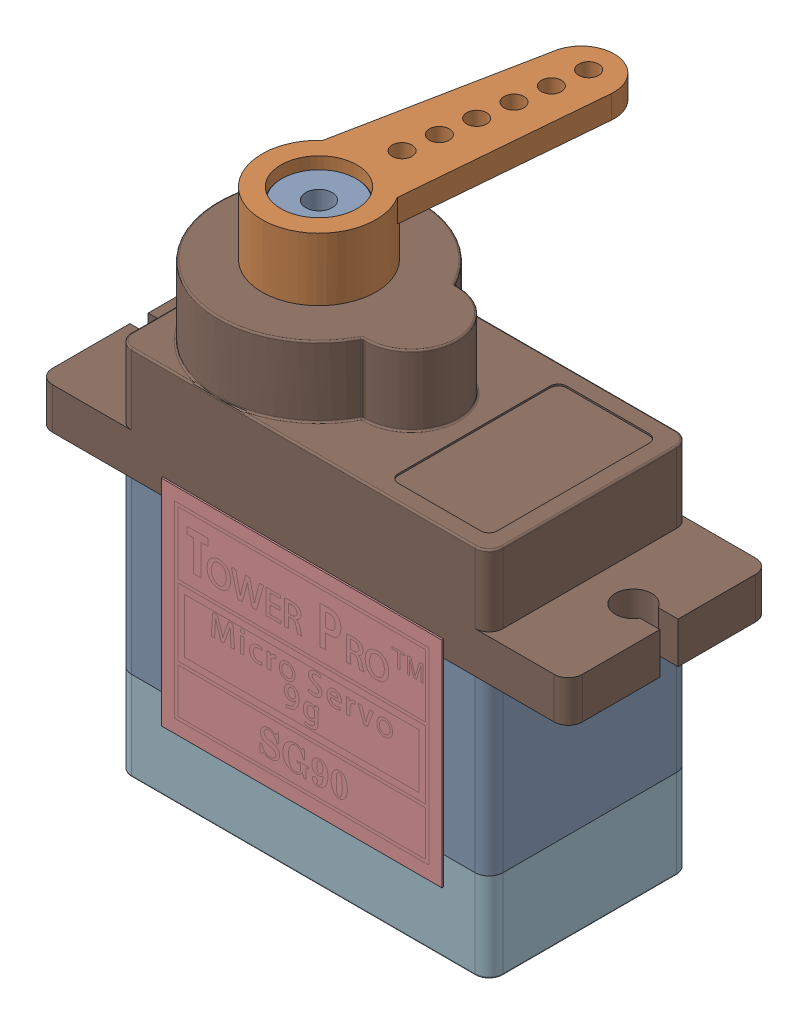
SolidWorks assembly ServoModelo1Completo, configuration Predeterminado. Lengths in mm.
Overall size (32.1 30.65 22.52).
2 component instances, 2 part files, 4 mates.
Components (placement in the parent):
- [4145] TowerPro SG90 Mini Servo-SunRobotics_in-Pt1-1: [4145] TowerPro SG90 Mini Servo-SunRobotics_in-Pt1 [Peça] at (-39.991 -0.898 1000) size (32.1 29.95 12.3)
- [4145] TowerPro SG90 Mini Servo-SunRobotics_in-Pt2-1: [4145] TowerPro SG90 Mini Servo-SunRobotics_in-Pt2 [Peça] at (-45.141 19.102 1000) x (-0.140373 0 0.990099) z (-0.990099 0 -0.140373) size (19.5 3.8 6.9)
Mates (geometry in assembly coordinates):
- Concéntrica1: concentric aligned: circle of [4145] TowerPro SG90 Mini Servo-SunRobotics_in-Pt1-1; circle of [4145] TowerPro SG90 Mini Servo-SunRobotics_in-Pt3-1
- Coincidente1: coincident anti-aligned: plane of [4145] TowerPro SG90 Mini Servo-SunRobotics_in-Pt1-1 through (-45.141 15.302 1000) normal (0 1 0); plane of [4145] TowerPro SG90 Mini Servo-SunRobotics_in-Pt3-1 through (-45.141 15.302 1000) normal (0 -1 0)
- Concéntrica2: concentric aligned: cylinder of [4145] TowerPro SG90 Mini Servo-SunRobotics_in-Pt1-1 through (-45.141 28.4316 1000) axis (0 -1 0) radius 2.45; cylinder of [4145] TowerPro SG90 Mini Servo-SunRobotics_in-Pt2-1 through (-45.141 15.302 1000) axis (0 -1 0) radius 2.475
- Coincidente2: coincident anti-aligned: plane of [4145] TowerPro SG90 Mini Servo-SunRobotics_in-Pt1-1 through (-45.141 15.302 1000) normal (0 1 0); plane of [4145] TowerPro SG90 Mini Servo-SunRobotics_in-Pt2-1 through (-45.141 15.302 1000) normal (0 -1 0)
